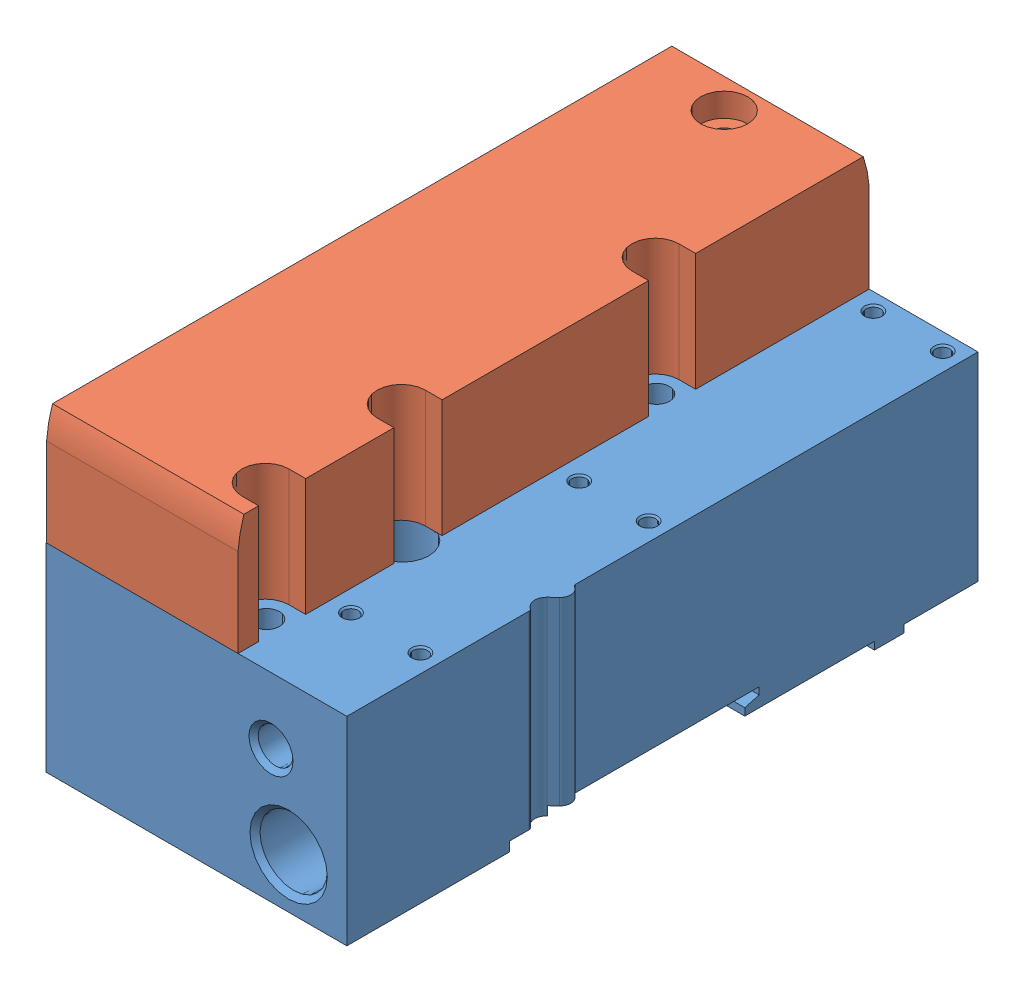
SolidWorks assembly 533370 VMPA-FB-EPL-G, configuration Default. Lengths in mm.
Overall size (55.83 45.1 107.3).
2 component instances, 2 part files, 0 mates.
Components (placement in the parent):
- 533370 VMPA-FB-EPL-G---(EPL)-1: 533370 VMPA-FB-EPL-G---(EPL) [Default] at origin size (52.3 35.1 107.3)
- VMPA-HBV---(HBV)-1: VMPA-HBV---(HBV) [Default] at (-12.25 35.1 0) size (32.55 20 107.3)
